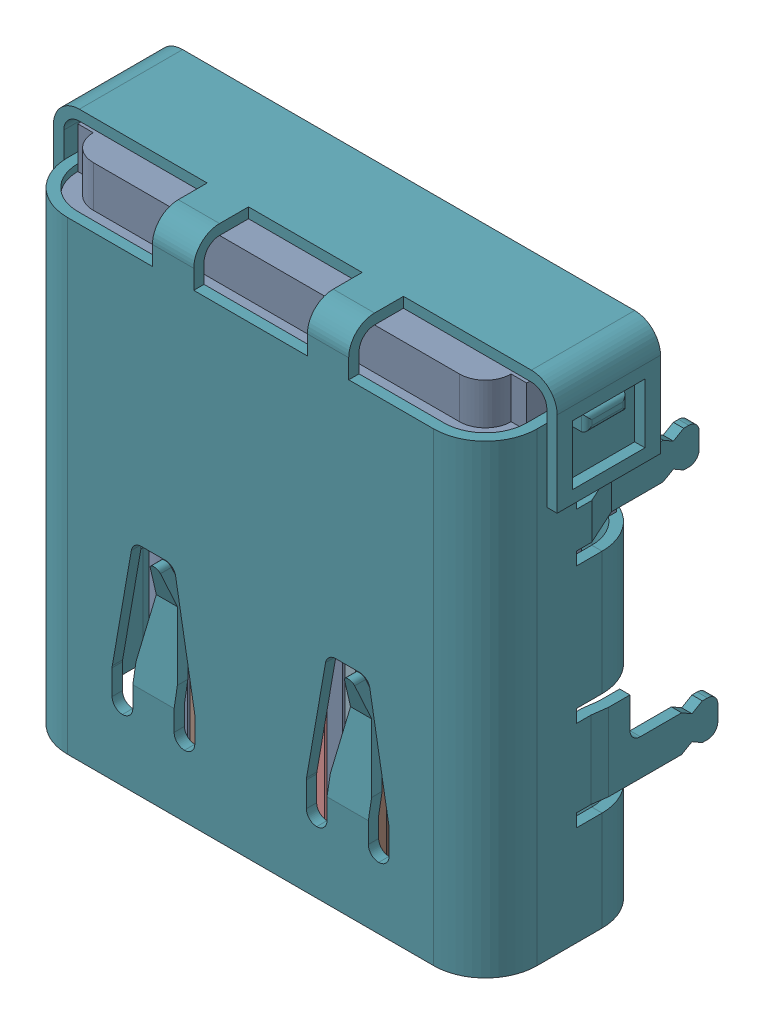
SolidWorks assembly KH-TYPE-C-24P-T9.87, configuration Défaut. Lengths in mm.
Overall size (9.75 9.87 4.46).
3 component instances, 1 part files, 0 mates.
Components (placement in the parent):
- 3D_PCB1_2021-12-30.step-1: 3D_PCB1_2021-12-30.step [Défaut] at origin size (9.75 9.87 4.46)
  - e9773ad0a1ba4615a8cdbe787346df90.step-1: e9773ad0a1ba4615a8cdbe787346df90.step [Défaut] at (5.0419 -6.8961 1.6) size (9.75 9.87 4.46)
    - COMPOUND.step_810-1: COMPOUND.step_810 [Défaut] at origin size (9.75 9.87 4.46)
